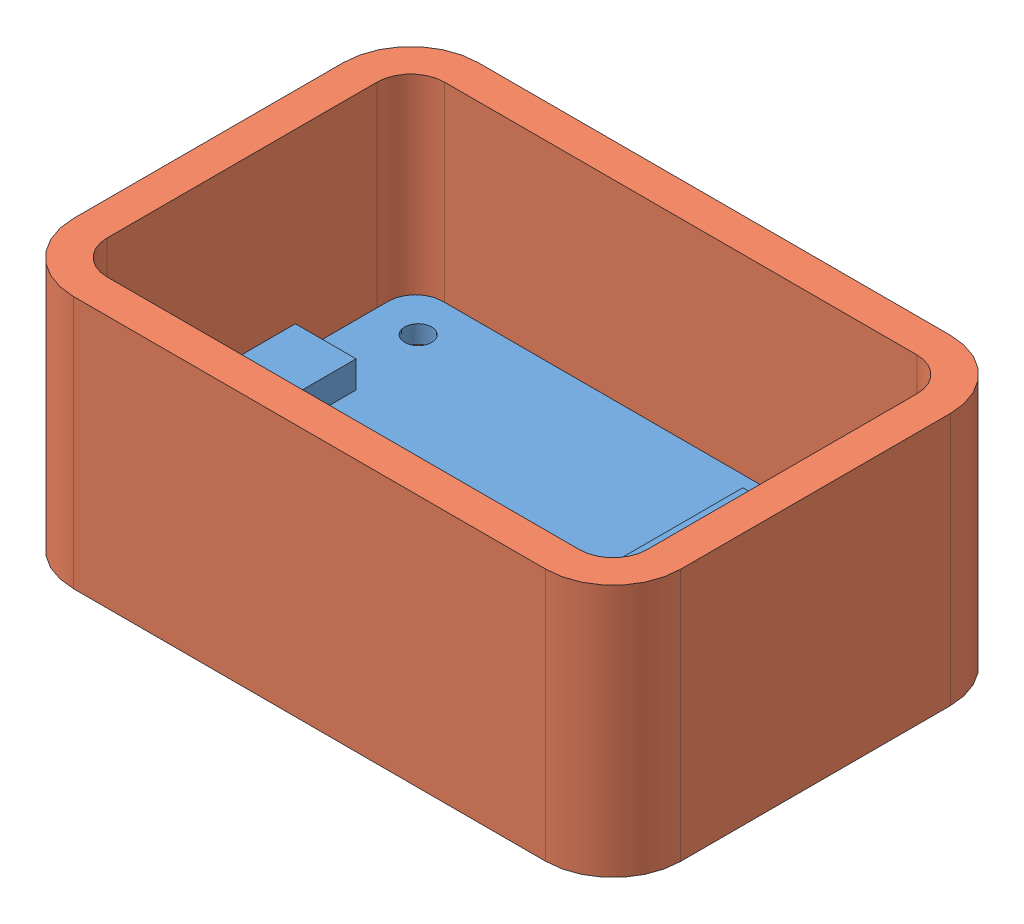
SolidWorks assembly Assem1, configuration Default. Lengths in mm.
Overall size (57.15 23.81 38.1).
2 component instances, 2 part files, 3 mates.
Components (placement in the parent):
- PCB, USB ISOLATOR-1: PCB, USB ISOLATOR [Default] at (-5.4625 25.6799 55.294) size (52.96 8.79 30.61)
- ISOLATOR, ENCLOSURE-1: ISOLATOR, ENCLOSURE [Default] at (18.9215 20.9174 39.9905) size (57.15 23.81 38.1)
Mates (geometry in assembly coordinates):
- Width1: width: plane of ISOLATOR, ENCLOSURE-1 through (41.1465 44.7299 24.1155) normal (0 0 1); plane of ISOLATOR, ENCLOSURE-1 through (-3.3035 44.7299 55.8655) normal (0 0 -1); plane of PCB, USB ISOLATOR-1 through (-5.4625 27.3563 24.687) normal (0 0 -1); plane of PCB, USB ISOLATOR-1 through (-5.4625 27.3563 55.294) normal (0 0 1)
- Coincident1: coincident: plane of PCB, USB ISOLATOR-1 through (-5.4625 25.6799 55.294) normal (0 -1 0); plane of ISOLATOR, ENCLOSURE-1 through (-3.3035 25.6799 52.6905) normal (0 1 0)
- Coincident2: coincident: plane of PCB, USB ISOLATOR-1 through (47.4965 34.4683 47.1025) normal (1 0 0); plane of ISOLATOR, ENCLOSURE-1 through (47.4965 25.6799 52.6905) normal (1 0 0)
